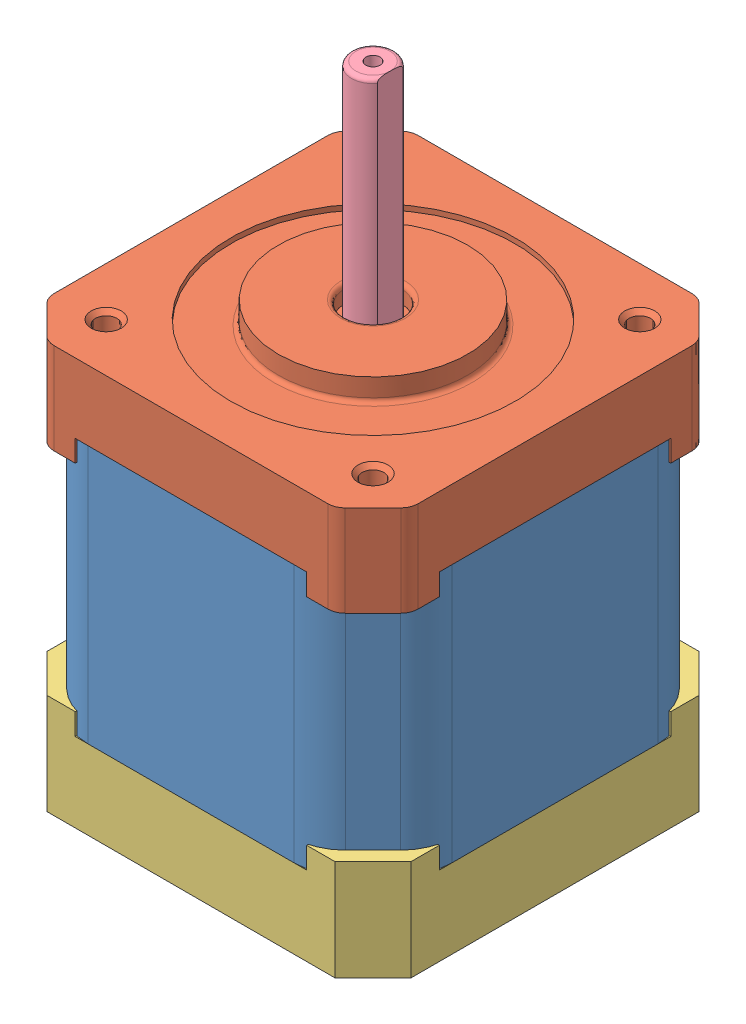
SolidWorks assembly Mandelbot_3_5_0_X_Nema17_StepperMotor_assembly_LDC+SMB_20171026_1806, configuration Default. Lengths in mm.
Overall size (54.28 73.5 54.28).
8 component instances, 5 part files, 16 mates.
Components (placement in the parent):
- 3-NEMA 17 Stepper Motor Middle3-1-1: 3-NEMA 17 Stepper Motor Middle3-1 [Default] at (-0.8591 0.1642 0.3418) size (42.3 30 42.3)
- 3-NEMA 17 Stepper Motor Top3-1-1: 3-NEMA 17 Stepper Motor Top3-1 [Default] at (-0.8591 12.6642 0.3418) size (42.3 12.6 42.3)
- 3-NEMA 17 Stepper Motor Bottom3-1-1: 3-NEMA 17 Stepper Motor Bottom3-1 [Default] at (-0.8591 -24.0358 0.3418) size (42.3 11.7 42.3)
- 3-NEMA 17 Stepper Motor Shaft3-1-1: 3-NEMA 17 Stepper Motor Shaft3-1 [Default] at (-0.8591 14.1142 0.3418) size (4.5 70.69 5)
- pan cross head_am-1: pan cross head_am [PreviewCfg] at (14.1409 -24.0358 15.3418) x (0 1 0) z (-0.99995 0 -0.010043) size (47.45 20 20)
- pan cross head_am-2: pan cross head_am [PreviewCfg] at (14.1409 -24.0358 -14.6582) x (0 1 0) z (-0.244235 0 0.969716) size (47.45 20 20)
- pan cross head_am-3: pan cross head_am [PreviewCfg] at (-15.8591 -24.0358 -14.6582) x (0 1 0) z (-0.244235 0 0.969716) size (47.45 20 20)
- pan cross head_am-4: pan cross head_am [PreviewCfg] at (-15.8591 -24.0358 15.3418) x (0 1 0) z (-0.244235 0 0.969716) size (47.45 20 20)
Mates (geometry in assembly coordinates):
- Coincident3: coincident: plane of assembly; plane of assembly; plane of 3-NEMA 17 Stepper Motor Middle3-1-1 through (-17.61 15.1642 21.4918) normal (0 0 1); plane of 3-NEMA 17 Stepper Motor Bottom3-1-1 through (-17.61 -12.3358 21.4918) normal (0 0 1)
- Coincident4: coincident: plane of assembly; plane of assembly; plane of 3-NEMA 17 Stepper Motor Middle3-1-1 through (-17.61 15.1642 21.4918) normal (0 0 1); plane of 3-NEMA 17 Stepper Motor Top3-1-1 through (-17.61 23.2642 21.4918) normal (0 0 1)
- Coincident5: coincident: plane of assembly; plane of assembly; plane of 3-NEMA 17 Stepper Motor Middle3-1-1 through (20.2909 15.1642 17.0927) normal (1 0 0); plane of 3-NEMA 17 Stepper Motor Bottom3-1-1 through (20.2909 -12.3358 17.0927) normal (1 0 0)
- Coincident6: coincident: plane of assembly; plane of assembly; plane of 3-NEMA 17 Stepper Motor Middle3-1-1 through (20.2909 15.1642 17.0927) normal (1 0 0); plane of 3-NEMA 17 Stepper Motor Top3-1-1 through (20.2909 23.2642 17.0927) normal (1 0 0)
- Coincident8: coincident: plane of assembly; plane of assembly; plane of 3-NEMA 17 Stepper Motor Middle3-1-1 through (-0.8591 15.1642 0.3418) normal (0 1 0); plane of 3-NEMA 17 Stepper Motor Top3-1-1 through (-14.31 15.1642 -20.8082) normal (0 -1 0)
- Coincident9: coincident: plane of assembly; plane of assembly; plane of 3-NEMA 17 Stepper Motor Middle3-1-1 through (-0.8591 -14.8358 0.3418) normal (0 -1 0); plane of 3-NEMA 17 Stepper Motor Bottom3-1-1 through (-22.0091 -14.8358 13.7927) normal (0 1 0)
- Concentric1: concentric: cylinder of 3-NEMA 17 Stepper Motor Top3-1-1 through (-0.8591 12.6642 0.3418) axis (0 1 0) radius 2.5; cylinder of 3-NEMA 17 Stepper Motor Shaft3-1-1 through (-0.8591 49.2642 0.3418) axis (0 -1 0) radius 2.5
- Coincident10: coincident: plane of assembly; plane of assembly; plane of 3-NEMA 17 Stepper Motor Bottom3-1-1 through (-0.8591 -21.0358 0.3418) normal (0 -1 0); plane of 3-NEMA 17 Stepper Motor Shaft3-1-1 through (-0.8591 -21.0358 0.3418) normal (0 -1 0)
- Concentric2: concentric: cylinder of 3-NEMA 17 Stepper Motor Bottom3-1-1 through (14.1409 -24.0358 15.3418) axis (0 -1 0) radius 1.45; cylinder of pan cross head_am-1 through (14.1409 -49.4358 15.3418) axis (0 -1 0) radius 5
- Concentric3: concentric: cylinder of 3-NEMA 17 Stepper Motor Bottom3-1-1 through (-15.8591 -24.0358 15.3418) axis (0 -1 0) radius 1.45; cylinder of pan cross head_am-4 through (-15.8591 -49.4358 15.3418) axis (0 -1 0) radius 5
- Concentric4: concentric: cylinder of 3-NEMA 17 Stepper Motor Bottom3-1-1 through (-15.8591 -24.0358 -14.6582) axis (0 -1 0) radius 1.45; cylinder of pan cross head_am-3 through (-15.8591 -49.4358 -14.6582) axis (0 -1 0) radius 5
- Concentric5: concentric: cylinder of 3-NEMA 17 Stepper Motor Bottom3-1-1 through (14.1409 -24.0358 -14.6582) axis (0 -1 0) radius 1.45; cylinder of pan cross head_am-2 through (14.1409 -49.4358 -14.6582) axis (0 -1 0) radius 5
- Coincident11: coincident: plane of 3-NEMA 17 Stepper Motor Bottom3-1-1 through (-14.4091 -21.9358 15.3418) normal (0 -1 0); plane of pan cross head_am-4 through (-20.7077 -16.5358 14.1206) normal (0 1 0)
- Coincident12: coincident: plane of 3-NEMA 17 Stepper Motor Bottom3-1-1 through (15.5909 -21.9358 15.3418) normal (0 -1 0); circle of pan cross head_am-1
- Coincident13: coincident: plane of 3-NEMA 17 Stepper Motor Bottom3-1-1 through (15.5909 -21.9358 -14.6582) normal (0 -1 0); plane of pan cross head_am-2 through (9.2923 -16.5358 -15.8794) normal (0 1 0)
- Coincident14: coincident: plane of 3-NEMA 17 Stepper Motor Bottom3-1-1 through (-14.4091 -21.9358 -14.6582) normal (0 -1 0); plane of pan cross head_am-3 through (-20.7077 -16.5358 -15.8794) normal (0 1 0)
